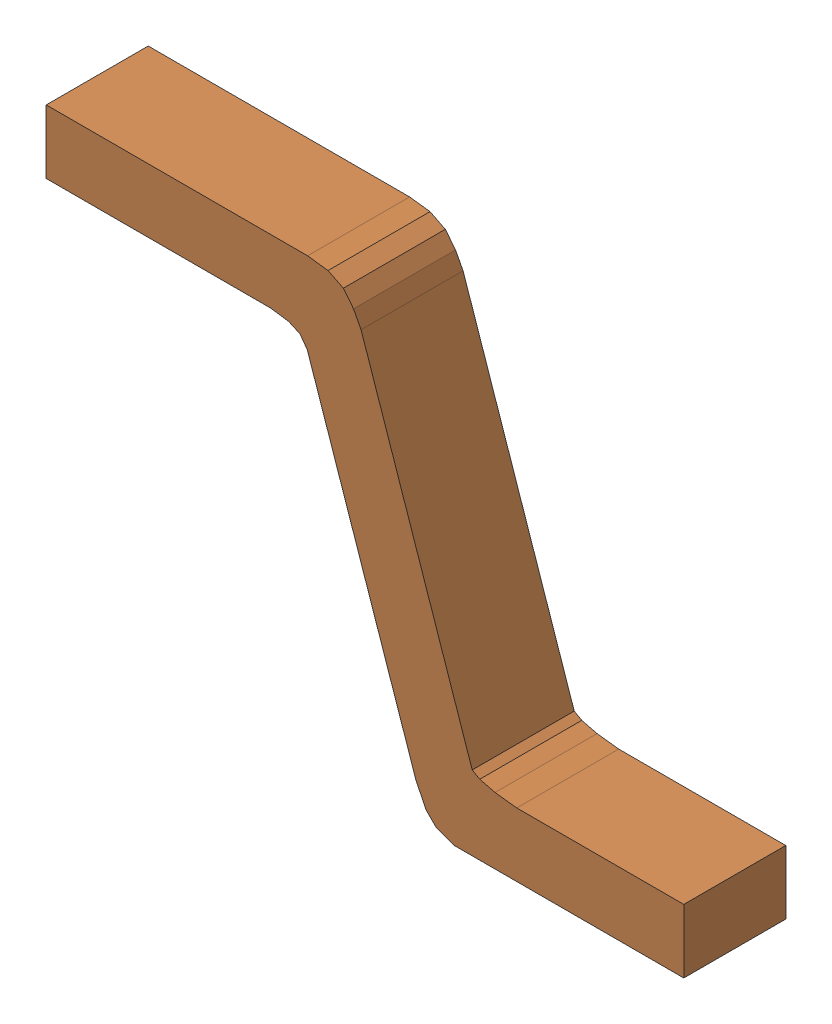
SolidWorks assembly SW3dPS-TO263-3S_PIN1, configuration Default. Lengths in mm.
Overall size (5 3.43 0.8).
4 component instances, 2 part files, 0 mates.
Components (placement in the parent):
- SW3dPS-TO263-3S_Board5-1: SW3dPS-TO263-3S_Board5 [Default] at (0 0 -0.0938) size (0.01 0.01 0.11)
- SW3dPS-TO263-3S_Free-Models6-1: SW3dPS-TO263-3S_Free-Models6 [Default] at origin size (5 3.43 0.8)
  - SW3dPS-TO263-3S_453496145-1: SW3dPS-TO263-3S_453496145 [Default] at (-2.4 1.465 -0.3873) size (5 3.43 0.8)
    - SW3dPS-TO263-3S_Extruded13-1: SW3dPS-TO263-3S_Extruded13 [Default] at origin size (5 3.43 0.8)
